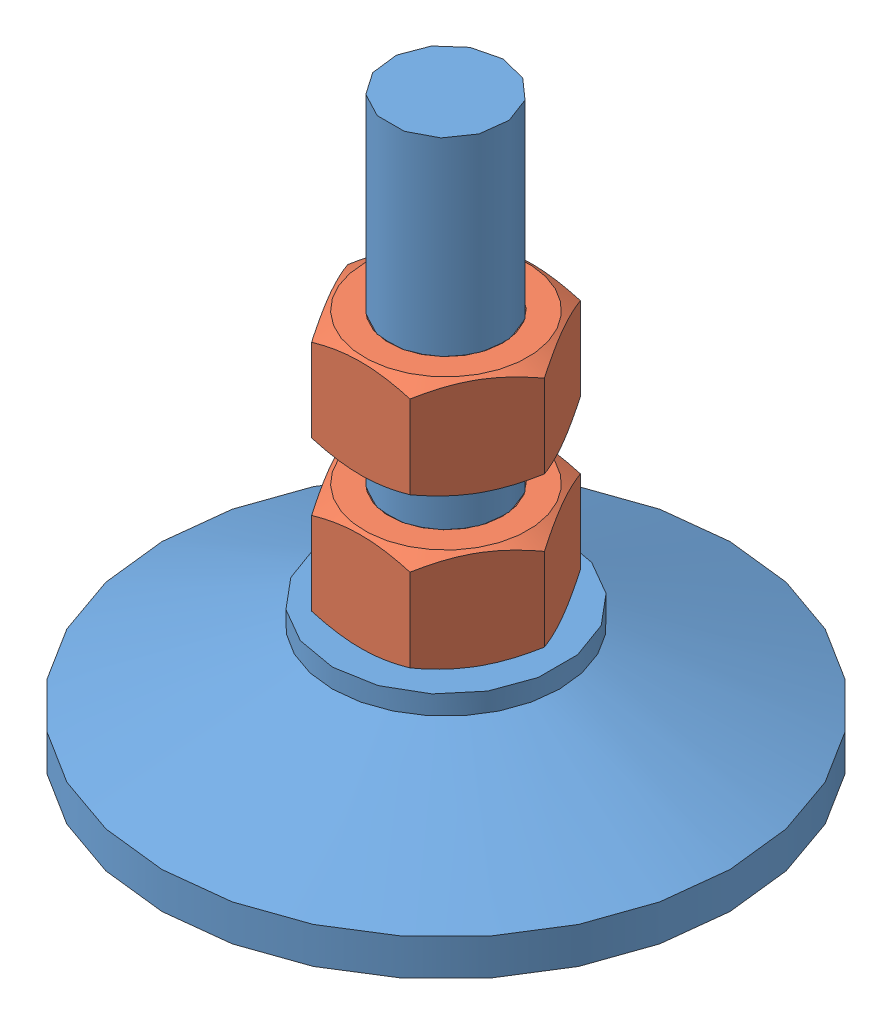
SolidWorks assembly 装配体5, configuration Default. Lengths in mm.
Overall size (60 60 60).
3 component instances, 2 part files, 4 mates.
Components (placement in the parent):
- footPole-1: footPole [Default] at origin size (60 60 60)
- GB_FASTENER_NUT_SNAB1 M12-C-1: GB_FASTENER_NUT_SNAB1 M12-C [GB_FASTENER_NUT_SNAB1 M12-C] at (0 24.1603 0) x (1 0 0) z (0 1 0) size (20.78 18 10.8)
- GB_FASTENER_NUT_SNAB1 M12-C-2: GB_FASTENER_NUT_SNAB1 M12-C [GB_FASTENER_NUT_SNAB1 M12-C] at (0 40 0) x (1 0 0) z (0 1 0) size (20.78 18 10.8)
Mates (geometry in assembly coordinates):
- 同心11: concentric anti-aligned: cylinder of footPole-1 through (0 0 0) axis (0 -1 0) radius 6; cone of GB_FASTENER_NUT_SNAB1 M12-C-1 through (0 13.3603 0) axis (0 1 0)
- 重合11: coincident anti-aligned: plane of footPole-1 through (0 13.3603 0) normal (0 1 0); plane of GB_FASTENER_NUT_SNAB1 M12-C-1 through (10.3923 13.3603 0) normal (0 -1 0)
- 同心2: concentric anti-aligned: cylinder of footPole-1 through (0 0 0) axis (0 -1 0) radius 6; cylinder of GB_FASTENER_NUT_SNAB1 M12-C-2 through (0 29.2 0) axis (0 1 0) radius 5.053
- 距离1: distance = 40 mm anti-aligned: plane of GB_FASTENER_NUT_SNAB1 M12-C-2 through (10.3923 40 0) normal (0 1 0); plane of footPole-1 through (0 0 0) normal (0 -1 0)
